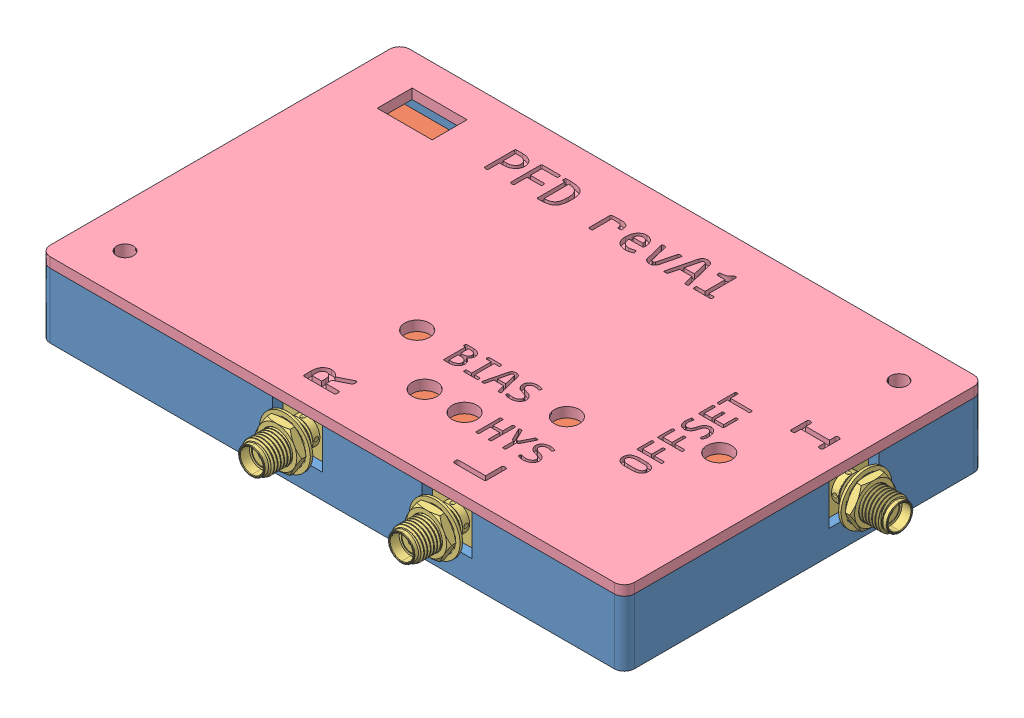
SolidWorks assembly PFD Enclosure, configuration Default. Lengths in mm.
Overall size (126.21 15 81.21).
6 component instances, 4 part files, 12 mates.
Components (placement in the parent):
- PFD Enclosure Base-1: PFD Enclosure Base [Default] at (-5.502 0 -5.4133) size (117 13 72)
- PFD Board Primitive-1: PFD Board Primitive [Default] at (-5.502 3.85 -5.4133) size (110 1.6 65)
- 132289-1: 132289 [Default] at (72.498 5.83 -5.4133) x (0 0 -1) z (1 0 0) size (17.46 10.21 10.21)
- 132289-2: 132289 [Default] at (104.498 5.83 -47.9133) x (-1 0 0) z (0 0 -1) size (17.46 10.21 10.21)
- 132289-3: 132289 [Default] at (42.498 5.83 -5.4133) x (0 0 -1) z (1 0 0) size (17.46 10.21 10.21)
- PFD Enclosure Lid-1: PFD Enclosure Lid [Default] at origin size (117 6.55 72)
Mates (geometry in assembly coordinates):
- Concentric1: concentric: cylinder of PFD Enclosure Base-1 through (99.498 -0.93 -65.4133) axis (0 1 0) radius 2; cylinder of PFD Board Primitive-1 through (99.498 5.45 -65.4133) axis (0 1 0) radius 2.25
- Concentric2: concentric: cylinder of PFD Enclosure Base-1 through (-0.502 -0.93 -10.4133) axis (0 1 0) radius 2; cylinder of PFD Board Primitive-1 through (-0.502 5.45 -10.4133) axis (0 1 0) radius 2.25
- Coincident2: coincident: plane of PFD Board Primitive-1 through (104.498 5.45 -5.4133) normal (1 0 0); plane of 132289-2 through (104.498 5.83 -47.9133) normal (-1 0 0)
- Coincident3: coincident: plane of PFD Board Primitive-1 through (-5.502 5.45 -5.4133) normal (0 0 1); plane of 132289-1 through (72.498 5.83 -5.4133) normal (0 0 -1)
- Coincident4: coincident: plane of PFD Board Primitive-1 through (-5.502 5.45 -5.4133) normal (0 0 1); plane of 132289-3 through (42.498 5.83 -5.4133) normal (0 0 -1)
- Coincident5: coincident: plane of PFD Board Primitive-1 through (-5.502 5.45 -5.4133) normal (0 1 0); plane of 132289-3 through (38.758 5.45 -5.4133) normal (0 -1 0)
- Coincident7: coincident: plane of PFD Board Primitive-1 through (-5.502 5.45 -5.4133) normal (0 1 0); plane of 132289-1 through (68.758 5.45 -5.4133) normal (0 -1 0)
- Coincident8: coincident: plane of PFD Board Primitive-1 through (-5.502 5.45 -5.4133) normal (0 1 0); plane of 132289-2 through (104.498 5.45 -52.6733) normal (0 -1 0)
- Distance1: distance = 27.24 mm: plane of 132289-1 through (77.258 1.87 -5.4133) normal (1 0 0); plane of PFD Board Primitive-1 through (104.498 5.45 -5.4133) normal (1 0 0)
- Distance2: distance = 57.24 mm: plane of 132289-3 through (47.258 1.87 -5.4133) normal (1 0 0); plane of PFD Board Primitive-1 through (104.498 5.45 -5.4133) normal (1 0 0)
- Distance3: distance = 37.74 mm: plane of PFD Board Primitive-1 through (-5.502 5.45 -5.4133) normal (0 0 1); plane of 132289-2 through (104.498 9.79 -43.1533) normal (0 0 1)
- Coincident13: coincident: plane of PFD Enclosure Base-1 through (99.498 3.85 -65.4133) normal (0 1 0); plane of PFD Board Primitive-1 through (-5.502 3.85 -5.4133) normal (0 -1 0)
